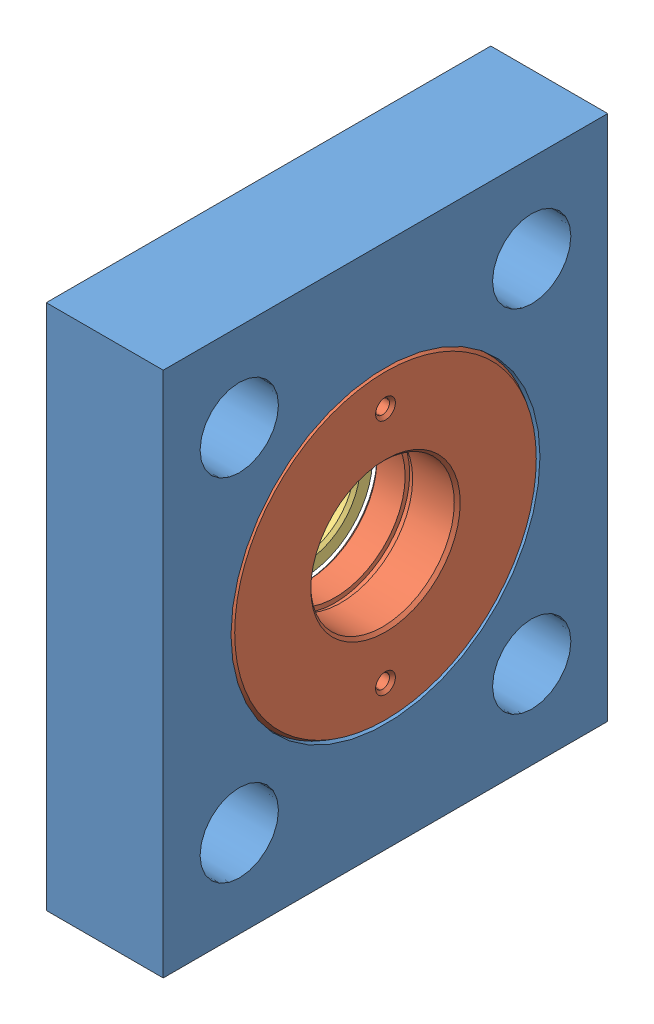
SolidWorks assembly collimation_len_assem, configuration Default. Lengths in mm.
Overall size (13.84 40 39).
3 component instances, 3 part files, 3 mates.
Components (placement in the parent):
- collimation lens plate-1: collimation lens plate [Default] at (10.0158 38.6264 34.7131) size (10 40 39)
- collimation_lens_adapter-1: collimation_lens_adapter [Default] at (16.5233 29.6326 31.3038) x (0 0 -1) z (1 0 0) size (26.29 26.29 6.99)
- collimation_lens-1: collimation_lens [Default] at (6.1728 29.6326 31.3038) size (6.86 12.24 12.24)
Mates (geometry in assembly coordinates):
- Concentric1: concentric aligned: circle of collimation lens plate-1; circle of collimation_lens_adapter-1
- Coincident1: coincident aligned: plane of collimation lens plate-1 through (20.0158 38.6264 34.7131) normal (1 0 0); plane of collimation_lens_adapter-1 through (20.0158 29.6326 31.3038) normal (1 0 0)
- Concentric2: concentric anti-aligned: circle of collimation_lens_adapter-1; circle of collimation_lens-1
